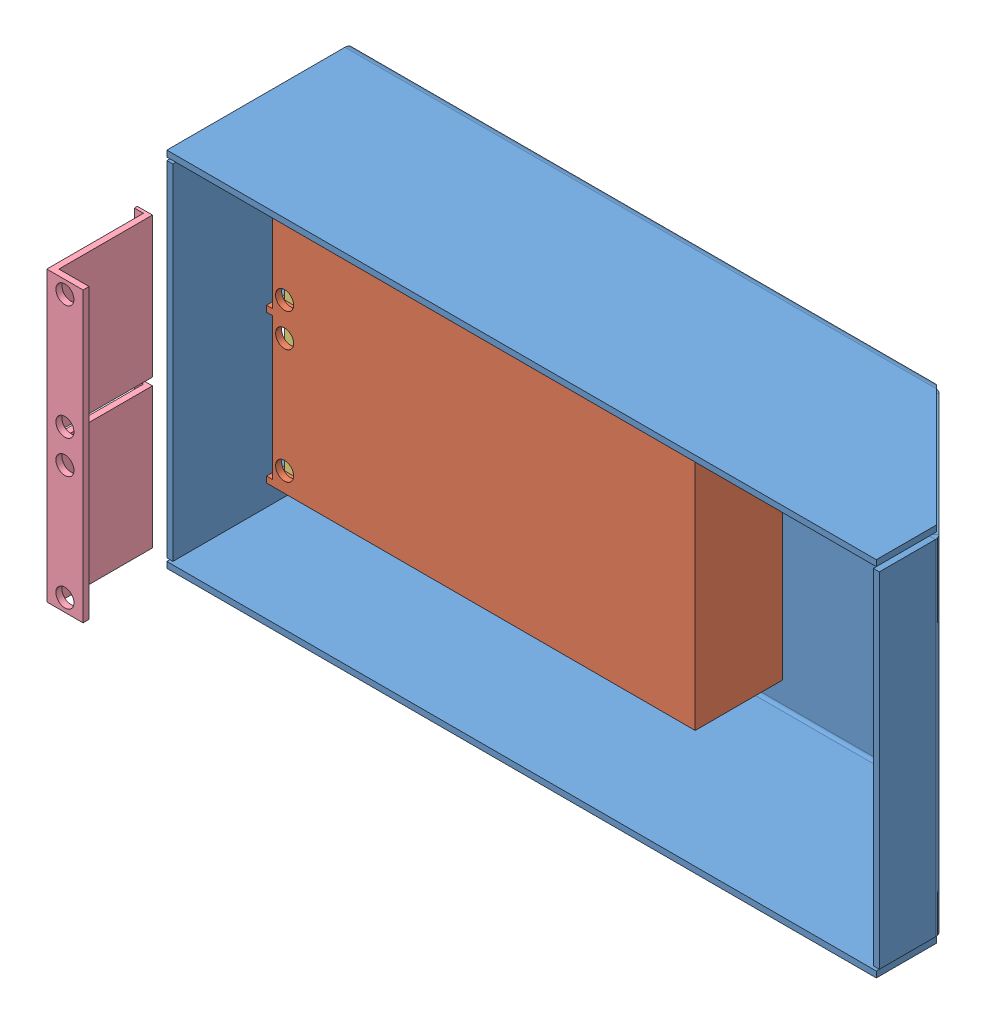
SolidWorks assembly bottom_assembly, configuration Default. Lengths in mm.
Overall size (237 120 103.76).
5 component instances, 4 part files, 11 mates.
Components (placement in the parent):
- bottom-1: bottom [Default] at (28.2004 13.8211 -36.241) size (236 120 62)
- battery_holder-1: battery_holder [Default] at (-76.1922 -17.8183 -7.241) x (1 0 0) z (0 0 -1) size (142 100 29)
- battery-1: battery [Default] at (-136.7436 9.892 -23.741) x (0 1 0) z (1 0 0) size (46 25 138)
- battery-2: battery [Default] at (-136.7436 -39.108 -23.741) x (0 1 0) z (1 0 0) size (46 25 138)
- battery_cover-1: battery_cover [Default] at (-138.7436 -12.8594 43.7741) x (0 1 0) z (1 0 0) size (95.5 33 15)
Mates (geometry in assembly coordinates):
- Coincident1: coincident anti-aligned: plane of bottom-1 through (28.2004 13.8211 -36.241) normal (0 0 1); plane of battery_holder-1 through (-76.1922 -17.8183 -36.241) normal (0 0 -1)
- Coincident2: coincident anti-aligned: plane of bottom-1 through (-138.7436 13.8211 -36.241) normal (1 0 0); plane of battery_holder-1 through (-138.7436 -64.608 -9.241) normal (-1 0 0)
- Coincident4: coincident aligned: plane of bottom-1 through (-140.7436 -62.608 -36.241) normal (0 1 0); plane of battery_holder-1 through (1.2564 -62.608 -36.241) normal (0 1 0)
- Coincident5: coincident anti-aligned: plane of bottom-1 through (28.2004 13.8211 -36.241) normal (0 0 1); plane of battery-1 through (1.2564 -13.108 -36.241) normal (0 0 -1)
- Coincident6: coincident anti-aligned: plane of battery_holder-1 through (1.2564 33.392 -36.241) normal (-1 0 0); plane of battery-1 through (1.2564 9.892 -23.741) normal (1 0 0)
- Distance2: distance = 0.5 mm anti-aligned: plane of battery_holder-1 through (-138.7436 -13.608 -36.241) normal (0 1 0); plane of battery-1 through (1.2564 -13.108 -11.241) normal (0 -1 0)
- Coincident8: coincident anti-aligned: plane of bottom-1 through (28.2004 13.8211 -36.241) normal (0 0 1); plane of battery-2 through (1.2564 -62.108 -36.241) normal (0 0 -1)
- Distance1: distance = 0.5 mm anti-aligned: plane of battery_holder-1 through (-138.7436 -15.608 -36.241) normal (0 -1 0); plane of battery-2 through (1.2564 -16.108 -11.241) normal (0 1 0)
- Coincident10: coincident anti-aligned: plane of battery_holder-1 through (1.2564 -15.608 -36.241) normal (-1 0 0); plane of battery-2 through (1.2564 -39.108 -23.741) normal (1 0 0)
- Coincident11: coincident anti-aligned: plane of bottom-1 through (-138.7436 13.8211 -36.241) normal (1 0 0); plane of battery_cover-1 through (-138.7436 -12.8594 43.7741) normal (-1 0 0)
- Distance3: distance = 0.25 mm anti-aligned: plane of battery_holder-1 through (1.2564 -62.608 -36.241) normal (0 1 0); plane of battery_cover-1 through (-136.7436 -62.358 32.5214) normal (0 -1 0)
